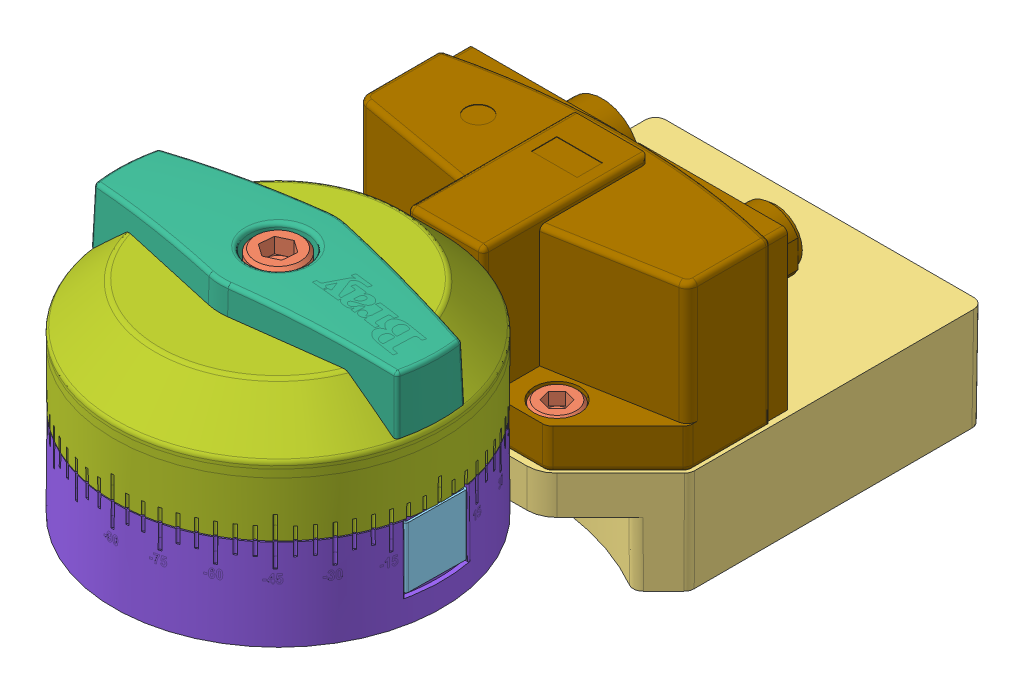
SolidWorks assembly Assem7, configuration Default. Lengths in mm.
Overall size (65.53 72.61 139.73).
13 component instances, 9 part files, 16 mates.
Components (placement in the parent):
- 07-5623-72107-1: 07-5623-72107 [Default] at (-501.2521 49.083 -507.7659) x (0 -1 0) z (0.643698 0 -0.76528) size (25 9.12 9.2)
- socket head cap screw_am-1: socket head cap screw_am [B18.3.1M - 5 x 0.8 x 12 Hex SHCS -- 12NHX] at (-471.251 60.4561 -482.766) x (0 -1 0) z (-0.706848 0 -0.707366) size (17 8.5 8.5)
- socket head cap screw_am-2: socket head cap screw_am [B18.3.1M - 6 x 1.0 x 30 Hex SHCS -- 30NHX] at (-486.2635 98.8675 -442.7386) x (0 -1 0) z (-0.995947 0 -0.089939) size (36 10 10)
- 54-160A-705S0-1: 54-160A-705S0 [Default] at (-486.3151 52.1513 -549.6806) x (-1 0 0.000958) z (-0.000958 0 -1) size (64.77 20.58 72.89)
- socket head cap screw_am-3: socket head cap screw_am [B18.3.1M - 5 x 0.8 x 12 Hex SHCS -- 12NHX] at (-501.276 60.4561 -482.766) x (0 -1 0) z (-0.706848 0 0.707366) size (17 8.5 8.5)
- 07-5623-72107-2: 07-5623-72107 [Default] at (-471.2749 49.083 -507.7659) x (0 -1 0) z (0.643698 0 0.76528) size (25 9.12 9.2)
- 54-160A-705P0-1: 54-160A-705P0 [Default] at (-486.2635 81.0057 -442.7386) size (45.64 22.89 45.64)
- 54-000A-73500-1: 54-000A-73500 [Default] at (-454.566 64.8307 -442.4047) x (0.011705 0 -0.999931) z (0.999931 0 0.011705) size (12.19 11.94 6.35)
- 54-000A-73500-2: 54-000A-73500 [Default] at (-485.9826 77.397 -474.9324) x (-1 -0.000194 0.00096) z (-0.000958 -0.008727 -0.999961) size (12.19 11.94 6.35)
- 54-000A-92512-1: 54-000A-92512 [Default] at (-486.2635 87.5335 -442.7386) x (-0.998952 0 -0.045767) z (0.045767 0 -0.998952) size (64.52 13.44 23.07)
- 54-000A-92511-1: 54-000A-92511 [Default] at (-486.2635 71.6585 -442.7386) x (-0.999932 0 -0.011665) z (0.011665 0 -0.999932) size (64.76 21.97 66.01)
- 54-000A-92510-1: 54-000A-92510 [Default] at (-486.2635 53.5737 -442.7386) x (0.011705 0 -0.999931) z (0.999931 0 0.011705) size (64.81 35.64 64.77)
- 54-0005-71104-1: 54-0005-71104 [Default] at (-486.2783 52.4561 -511.2516) x (1 0 -0.000958) z (0.000958 0 1) size (65 33.5 48.75)
Mates (geometry in assembly coordinates):
- Coincident1: coincident: plane of 54-000A-92511-1 through (-486.4103 84.1807 -430.1538) normal (0 -1 0); plane of 54-000A-92510-1 through (-486.1134 84.1807 -455.5647) normal (0 1 0)
- Coincident2: coincident: plane of socket head cap screw_am-2 through (-486.7132 92.8675 -437.7589) normal (0 -1 0); plane of 54-000A-92512-1 through (-486.5152 92.8675 -437.2444) normal (0 1 0)
- Parallel1: parallel: line of 54-000A-73500-1 through (-455.1708 58.8617 -436.3153) axis (0 1 0); plane of 54-000A-92510-1 through (-455.9085 53.5737 -436.2234) normal (0.046595 0 -0.998914)
- Coincident3: coincident: line of 54-000A-73500-2 through (-492.0778 79.6315 -473.676) axis (-0.000203 0.999962 -0.008726); plane of 54-000A-92511-1 through (-492.0676 71.6585 -473.2376) normal (0.99973 0 -0.023239)
- Coincident4: coincident: plane of 54-160A-705P0-1 through (-486.2635 81.0057 -442.7386) normal (0 1 0); plane of 54-000A-92510-1 through (-486.0123 81.0057 -464.2001) normal (0 -1 0)
- Coincident5: coincident: plane of 54-000A-73500-1 through (-455.7646 70.7997 -448.5151) normal (-0.999931 0 -0.011705); plane of 54-000A-92510-1 through (-455.8364 53.5737 -442.3824) normal (0.999931 0 0.011705)
- Parallel2: parallel: plane of 54-160A-705S0-1 through (-453.9301 52.1513 -549.7116) normal (-0.000958 -0.008727 -0.999961); plane of 54-000A-73500-2 through (-479.8878 83.367 -474.9903) normal (-0.000958 -0.008727 -0.999961)
- Concentric1: concentric: cylinder of 54-160A-705P0-1 through (-486.2635 90.3395 -442.7386) axis (0 -1 0) radius 3.3; cylinder of 54-000A-92510-1 through (-486.2635 44.2399 -442.7386) axis (0 1 0) radius 3.3
- Concentric2: concentric: cylinder of 54-000A-92512-1 through (-486.2635 87.5335 -442.7386) axis (0 -1 0) radius 3.3; cylinder of 54-000A-92511-1 through (-486.2635 74.8469 -442.7386) axis (0 1 0) radius 3.3
- Distance1: distance = 0.1778 mm: plane of 54-000A-92511-1 through (-486.3805 87.3557 -432.7063) normal (0 1 0); plane of 54-000A-92512-1 through (-486.6024 87.5335 -435.3423) normal (0 -1 0)
- Concentric3: concentric: cylinder of 54-000A-92511-1 through (-486.2635 74.8469 -442.7386) axis (0 1 0) radius 3.3; cylinder of 54-000A-92510-1 through (-486.2635 44.2399 -442.7386) axis (0 1 0) radius 3.3
- Concentric4: concentric: cylinder of 54-160A-705S0-1 through (-471.2749 52.1513 -507.7659) axis (0 1 0) radius 2.8067; cylinder of 07-5623-72107-2 through (-471.2749 48.283 -507.7659) axis (0 -1 0) radius 2.5
- Concentric5: concentric: cylinder of socket head cap screw_am-2 through (-486.2635 130.6175 -442.7386) axis (0 1 0) radius 3; cylinder of 54-000A-92511-1 through (-486.2635 74.8469 -442.7386) axis (0 1 0) radius 3.3
- Concentric6: concentric: circle of 54-160A-705S0-1; circle of 07-5623-72107-2
- Concentric7: concentric: cone of 54-160A-705S0-1 through (-471.2749 52.1513 -507.7659) axis (0 -1 0); cone of 07-5623-72107-2 through (-471.2749 51.333 -507.7659) axis (0 -1 0)
- Concentric8: concentric: circle of 54-160A-705S0-1; circle of 07-5623-72107-2
